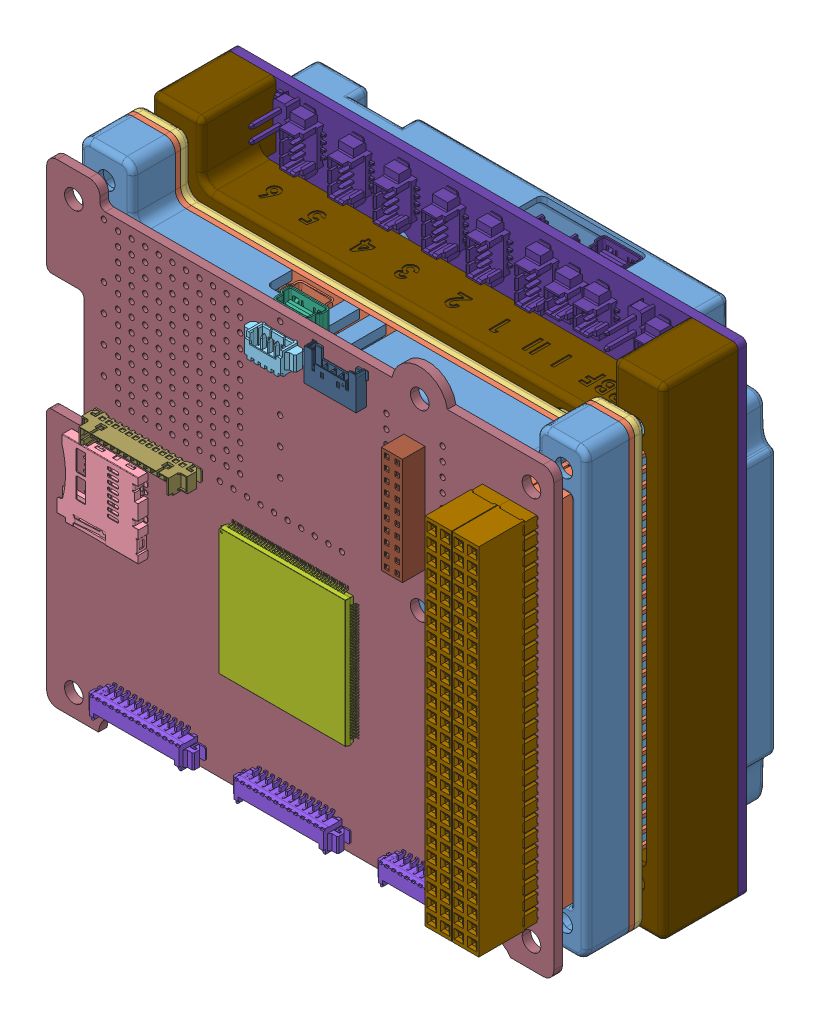
SolidWorks assembly Endurosat_Internal, configuration Default. Lengths in mm.
Overall size (98.18 90.37 51.86).
56 component instances, 21 part files, 6 mates.
Components (placement in the parent):
- UHF_comm_type_II.STEP-1: UHF_comm_type_II.STEP [Default] at (27.1151 12.3666 -17.6788) size (97.88 89.01 26.68)
  - UHF_BOX.STEP-1: UHF_BOX.STEP [Default] at (-90.205 -23.549 76.8824) size (95 89 8.01)
  - UHF_PCB_STEP.STEP-1: UHF_PCB_STEP.STEP [Default] at (-39.659 9.6582 83.8824) size (97.88 89.01 26.68)
  - UHF_BOX-bottom-part(nif).STEP-1: UHF_BOX-bottom-part(nif).STEP [Default] at (-24.9069 125.9519 81.8824) x (1 0 0) z (0 -1 0) size (95 2.01 89)
- OBC_EnduroSat.STEP-1: OBC_EnduroSat.STEP [Default] at (-12.5439 22.0248 80.3036) x (1 0 0) z (0 0 1) size (95 89.38 23.24)
  - SD1021117.STEP-1: SD1021117.STEP [Default] at origin size (15.2 14.1 1.88)
    - User_Library-473521001_microSD.STEP-1: User_Library-473521001_microSD.STEP [Default] at (11.4631 39.834 0.9) x (0 -1 0) z (0 0 1) size (14.1 15.2 1.88)
  - P1021117.STEP-1: P1021117.STEP [Default] at origin size (10.15 5.2 3.4)
    - MOLEX_Pico_Blade_532610471.STEP-1: MOLEX_Pico_Blade_532610471.STEP [Default] at (43.8404 79.9325 1.7) size (10.15 5.2 3.4)
      - Open CASCADE STEP translator 6.8 1.14.1.1.STEP-1: Open CASCADE STEP translator 6.8 1.14.1.1.STEP [Default] at origin size (10.15 5.2 3.4)
  - USB1021117.STEP-1: USB1021117.STEP [Default] at origin size (9.9 9.22 5.09)
    - USB_Mini_B_SMT_Horisontal.STEP-1: USB_Mini_B_SMT_Horisontal.STEP [Default] at (43.8628 84.9308 -3.6122) x (1 0 0) z (0 1 0) size (9.9 5.09 9.22)
  - U1021117.STEP-1: U1021117.STEP [Default] at origin size (25.77 25.77 1.57)
    - User_Library-LQFP176-0_5.STEP-1: User_Library-LQFP176-0_5.STEP [Default] at (45.653 34.1752 0.75) x (1 0 0) z (0 0 1) size (25.77 25.77 1.57)
  - PAN6021117.STEP-1: PAN6021117.STEP [Default] at origin size (20.15 5.2 3.5)
    - MOLEX_Pico_Blade_532611271.STEP-1: MOLEX_Pico_Blade_532611271.STEP [Default] at (74.0242 8.708 -1.6) x (-1 0 0) z (0 0 -1) size (20.15 5.2 3.5)
  - PAN5021117.STEP-1: PAN5021117.STEP [Default] at origin size (20.15 5.2 3.5)
    - MOLEX_Pico_Blade_532611271.STEP-1: MOLEX_Pico_Blade_532611271.STEP [Default] at (46.9392 8.708 -1.6) x (-1 0 0) z (0 0 -1) size (20.15 5.2 3.5)
  - PAN4021117.STEP-1: PAN4021117.STEP [Default] at origin size (20.15 5.2 3.5)
    - MOLEX_Pico_Blade_532611271.STEP-1: MOLEX_Pico_Blade_532611271.STEP [Default] at (19.8882 8.708 -1.6) x (-1 0 0) z (0 0 -1) size (20.15 5.2 3.5)
  - PAN3021117.STEP-1: PAN3021117.STEP [Default] at origin size (20.15 5.2 3.5)
    - MOLEX_Pico_Blade_532611271.STEP-1: MOLEX_Pico_Blade_532611271.STEP [Default] at (73.9902 8.708 0) x (1 0 0) z (0 0 1) size (20.15 5.2 3.5)
  - PAN2021117.STEP-1: PAN2021117.STEP [Default] at origin size (20.15 5.2 3.5)
    - MOLEX_Pico_Blade_532611271.STEP-1: MOLEX_Pico_Blade_532611271.STEP [Default] at (46.9392 8.708 0) size (20.15 5.2 3.5)
  - PAN1021117.STEP-1: PAN1021117.STEP [Default] at origin size (20.15 5.2 3.5)
    - MOLEX_Pico_Blade_532611271.STEP-1: MOLEX_Pico_Blade_532611271.STEP [Default] at (19.8882 8.708 0) size (20.15 5.2 3.5)
  - H2021117.STEP-1: H2021117.STEP [Default] at origin size (5.08 66.55 23.24)
    - Samtec-ESQ-126-14-G-D.STEP-1: Samtec-ESQ-126-14-G-D.STEP [Default] at (89.5246 43.45 2.5522) x (-1 0 0) z (0 1 0) size (5.08 23.24 66.55)
  - H1021117.STEP-1: H1021117.STEP [Default] at origin size (5.08 66.55 23.24)
    - Samtec-ESQ-126-14-G-D.STEP-1: Samtec-ESQ-126-14-G-D.STEP [Default] at (84.4446 43.45 2.5522) x (-1 0 0) z (0 1 0) size (5.08 23.24 66.55)
  - J1021117.STEP-1: J1021117.STEP [Default] at origin size (10.55 6.44 2)
    - 5040500491.STEP-1: 5040500491.STEP [Default] at (55.0672 77.863 1) x (1 0 0) z (0 0 1) size (10.55 6.44 2)
      - Open CASCADE STEP translator 6.8 1.245.1.1.STEP-1: Open CASCADE STEP translator 6.8 1.245.1.1.STEP [Default] at origin size (10.55 6.44 2)
  - JP2021117.STEP-1: JP2021117.STEP [Default] at origin size (5.56 20 4.5)
    - Samtec-TLE-110-01-G-DV.STEP-1: Samtec-TLE-110-01-G-DV.STEP [Default] at (68.9102 66.945 2.0874) x (0 1 0) z (1 0 0) size (20 4.5 5.56)
  - JP14021117.STEP-1: JP14021117.STEP [Default] at origin size (5.56 20 4.5)
    - Samtec-TLE-110-01-G-DV.STEP-1: Samtec-TLE-110-01-G-DV.STEP [Default] at (68.8848 66.945 -3.6873) x (0 1 0) z (-1 0 0) size (20 4.5 5.56)
  - JP15021117.STEP-1: JP15021117.STEP [Default] at origin size (20.15 4.2 4.7)
    - User_Library-molex_53398_1271.STEP-1: User_Library-molex_53398_1271.STEP [Default] at (19.1599 50.8269 0) x (1 0 0) z (0 0 1) size (20.15 4.2 4.7)
  - Board021117.STEP-1: Board021117.STEP [Default] at origin size (95 89.38 1.6)
- EPS1 - Battery.STEP-1: EPS1 - Battery.STEP [Default] at (10.3437 18.3225 -33.4897) x (1 0 0) z (0 0 1) size (95.9 90.21 21.2)
  - ESQ_126_37_G_D.STEP-1: ESQ_126_37_G_D.STEP [Default] at (61.557 47.1532 82.7332) x (0 1 0) z (1 0 0) size (66.55 13.33 5.08)
    - _ESQ_126_37_G_D_socket_2.STEP-1: _ESQ_126_37_G_D_socket_2.STEP [Default] at (-33.274 0 0) size (66.55 8.51 4.95)
    - _ESQ_126_37_G_D_pins_4.STEP-1: _ESQ_126_37_G_D_pins_4.STEP [Default] at origin size (65.79 9.77 4.7)
    - _ESQ_126_37_G_D_LL_bpins_6.STEP-1: _ESQ_126_37_G_D_LL_bpins_6.STEP [Default] at (-33.147 -2.54 0) size (66.04 2.54 5.08)
  - ESQ_126_37_G_D.STEP-2: ESQ_126_37_G_D.STEP [Default] at (66.637 47.1532 82.7332) x (0 1 0) z (1 0 0) size (66.55 13.33 5.08)
    - _ESQ_126_37_G_D_socket_2.STEP-1: _ESQ_126_37_G_D_socket_2.STEP [Default] at (-33.274 0 0) size (66.55 8.51 4.95)
    - _ESQ_126_37_G_D_pins_4.STEP-1: _ESQ_126_37_G_D_pins_4.STEP [Default] at origin size (65.79 9.77 4.7)
    - _ESQ_126_37_G_D_LL_bpins_6.STEP-1: _ESQ_126_37_G_D_LL_bpins_6.STEP [Default] at (-33.147 -2.54 0) size (66.04 2.54 5.08)
  - ES_EPS_Rev1_4_PCB_STEP.STEP-1: ES_EPS_Rev1_4_PCB_STEP.STEP [Default] at (-22.8876 2.7023 80.1932) size (95.9 90.21 13.97)
  - top-cover_EPS1.STEP-1: top-cover_EPS1.STEP [Default] at (-22.8876 2.7023 80.1932) size (95.9 90.2 14)
  - bottom-cover_Rev1.2.STEP-1: bottom-cover_Rev1.2.STEP [Default] at (25.0624 47.8023 72.9932) size (95.9 90.2 13.5)
  - TR Fastenings Ltd-M2_5X4mm.STEP-1: TR Fastenings Ltd-M2_5X4mm.STEP [Default] at (-22.8876 68.8523 83.4832) x (0 0.841973 -0.539519) z (-1 0 0) size (4.7 4.7 4)
  - TR Fastenings Ltd-M2_5X4mm.STEP-2: TR Fastenings Ltd-M2_5X4mm.STEP [Default] at (-22.8876 26.7523 83.4832) x (0 0.924225 0.381849) z (-1 0 0) size (4.7 4.7 4)
  - 965 M3x6 Torx_M3X6mm.STEP-1: 965 M3x6 Torx_M3X6mm.STEP [Default] at (54.8324 9.3023 93.4576) x (0.993054 -0.117656 0) z (0 0 1) size (5.5 5.5 6)
  - 965 M3x6 Torx_M3X6mm.STEP-2: 965 M3x6 Torx_M3X6mm.STEP [Default] at (54.8324 77.0023 93.4697) x (0.987647 0.156698 0) z (0 0 1) size (5.5 5.5 6)
Mates (geometry in assembly coordinates):
- Concentric1: concentric anti-aligned: circle of UHF_comm_type_II.STEP-1/UHF_BOX-bottom-part(nif).STEP-1; circle of EPS1 - Battery.STEP-1/ES_EPS_Rev1_4_PCB_STEP.STEP-1
- Concentric2: concentric anti-aligned: circle of UHF_comm_type_II.STEP-1/UHF_BOX-bottom-part(nif).STEP-1; circle of EPS1 - Battery.STEP-1/ES_EPS_Rev1_4_PCB_STEP.STEP-1
- Concentric3: concentric aligned: circle of OBC_EnduroSat.STEP-1/Board021117.STEP-1; circle of EPS1 - Battery.STEP-1/ES_EPS_Rev1_4_PCB_STEP.STEP-1
- Concentric4: concentric anti-aligned: circle of OBC_EnduroSat.STEP-1/Board021117.STEP-1; circle of EPS1 - Battery.STEP-1/top-cover_EPS1.STEP-1
- Distance2: distance = 2.5 mm anti-aligned: plane of UHF_comm_type_II.STEP-1/UHF_BOX-bottom-part(nif).STEP-1 through (1.4561 21.7248 63.2036) normal (0 0 -1); plane of EPS1 - Battery.STEP-1/top-cover_EPS1.STEP-1 through (82.3561 22.0248 60.7036) normal (0 0 1)
- Distance1: distance = 4.5 mm anti-aligned: plane of OBC_EnduroSat.STEP-1/Board021117.STEP-1 through (-12.5439 24.0248 78.7036) normal (0 0 -1); plane of UHF_comm_type_II.STEP-1/UHF_BOX.STEP-1 through (80.4561 26.021 74.2036) normal (0 0 1)
